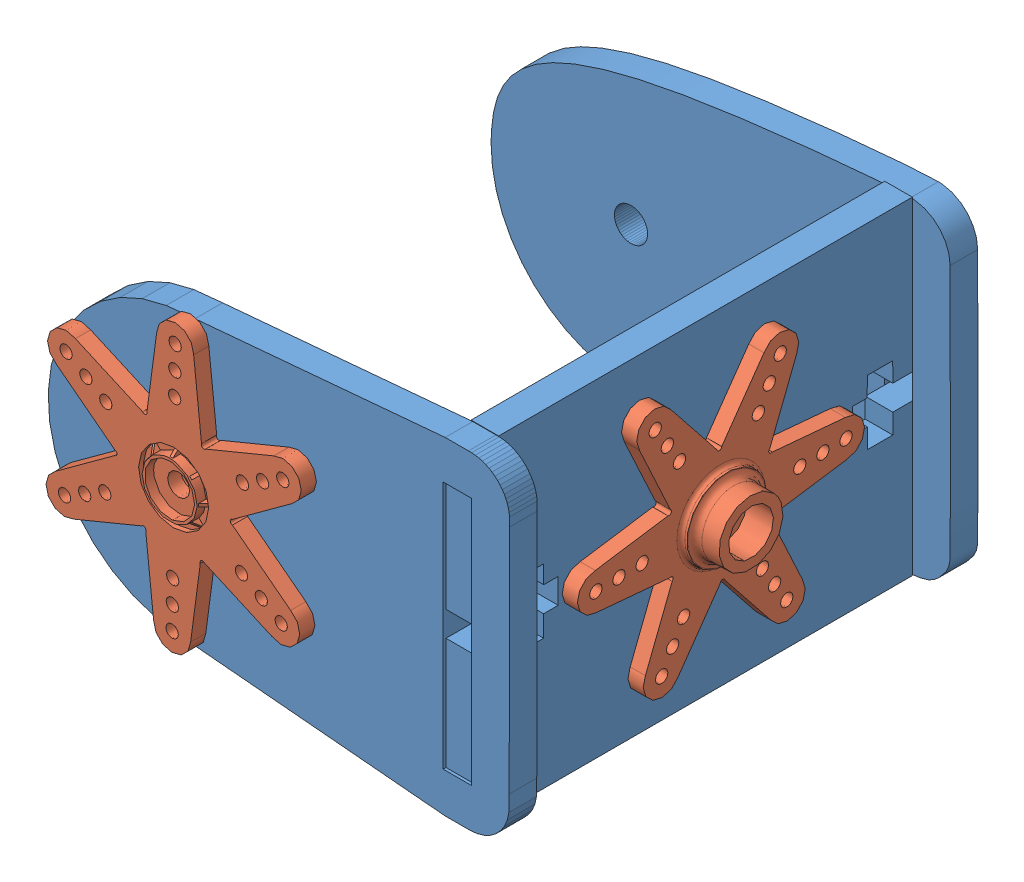
SolidWorks assembly right_shoulder, configuration Default. Lengths in mm.
Overall size (63.84 49.25 61.92).
3 component instances, 2 part files, 2 mates.
Components (placement in the parent):
- right_shoulder_100-1: right_shoulder_100 [Default] at (-15.0555 5.0614 22.6229) size (63.18 46.66 59.49)
- servo_arm_6_sided-1: servo_arm_6_sided [Default] at (2.7995 34.1696 82.1085) x (-0.012285 -0.999925 0) z (-0.999925 0.012285 0) size (36.45 6.25 32.2)
- servo_arm_6_sided-2: servo_arm_6_sided [Default] at (40.5758 34.2055 52.3734) x (0 0.85063 0.525765) z (0 -0.525765 0.85063) size (36.45 6.25 32.2)
Mates (geometry in assembly coordinates):
- Concentric1: concentric aligned: circle of right_shoulder_100-1; circle of servo_arm_6_sided-1
- Concentric2: concentric aligned: circle of right_shoulder_100-1; circle of servo_arm_6_sided-2
